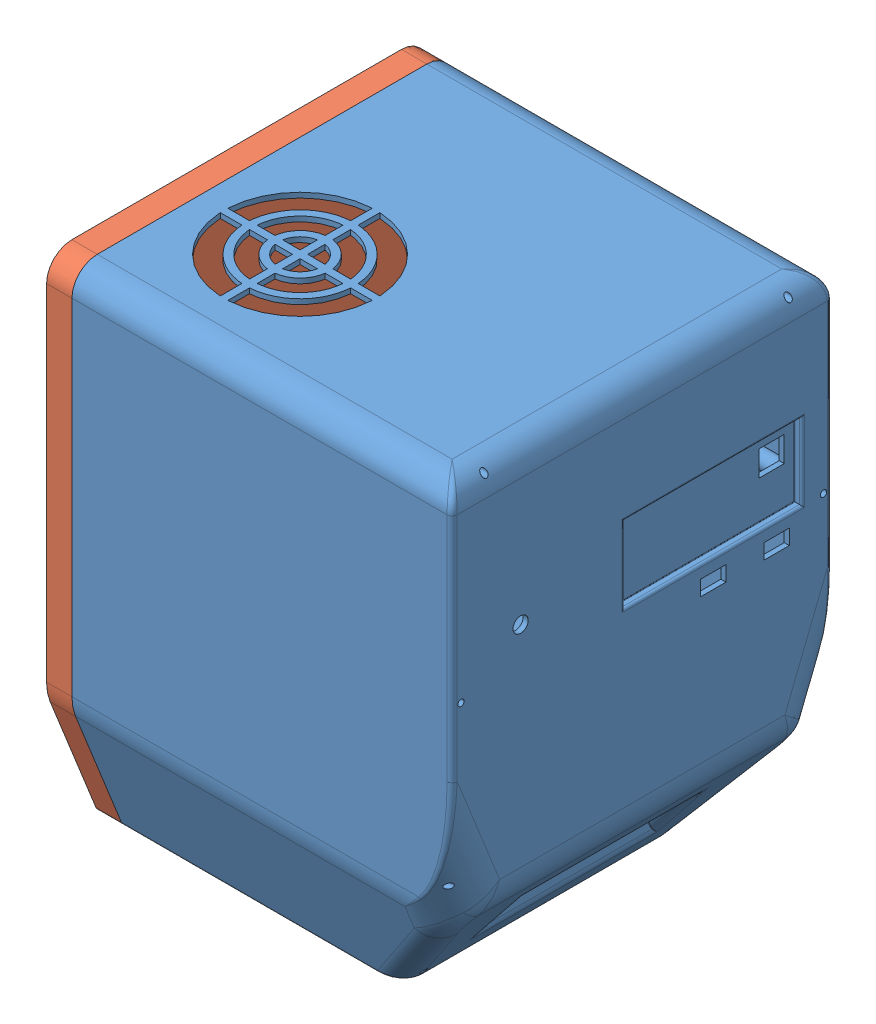
SolidWorks assembly Assem1, configuration Default. Lengths in mm.
Overall size (160 200.01 150).
2 component instances, 2 part files, 4 mates.
Components (placement in the parent):
- EDR part 1-1: EDR part 1 [Default] at origin size (150 200.01 150)
- Back lid-1: Back lid [Default] at (-75 0 0) x (0 0 1) z (-1 0 0) size (150 200 10)
Mates (geometry in assembly coordinates):
- InPlace1: in place: plane of EDR part 1-1 through (-75 200 -75) normal (-1 0 0); plane of Back lid-1 through (-75 0 0) normal (-1 0 0); moOrthogonalPlaneRef_w of EDR part 1-1 through (-75 200 -75) normal (-1 0 0); plane of Back lid-1 through (-75 0 0) normal (0 1 0); plane of EDR part 1-1 through (-75 200 -75) normal (-1 0 0); plane of Back lid-1 through (-75 0 0) normal (0 0 1); plane of EDR part 1-1 through (-75 200 -75) normal (-1 0 0); unknown of Back lid-1
- Coincident1: coincident aligned: plane of EDR part 1-1; plane of Back lid-1
- Coincident2: coincident aligned: moOrthogonalPlaneRef_w of EDR part 1-1 through (-75 0 0) normal (0 1 0); plane of Back lid-1 through (-75 0 0) normal (0 1 0)
- Coincident3: coincident anti-aligned: moOrthogonalPlaneRef_w of EDR part 1-1 through (-75 0 0) normal (0 0 -1); plane of Back lid-1 through (-75 0 0) normal (0 0 1)
